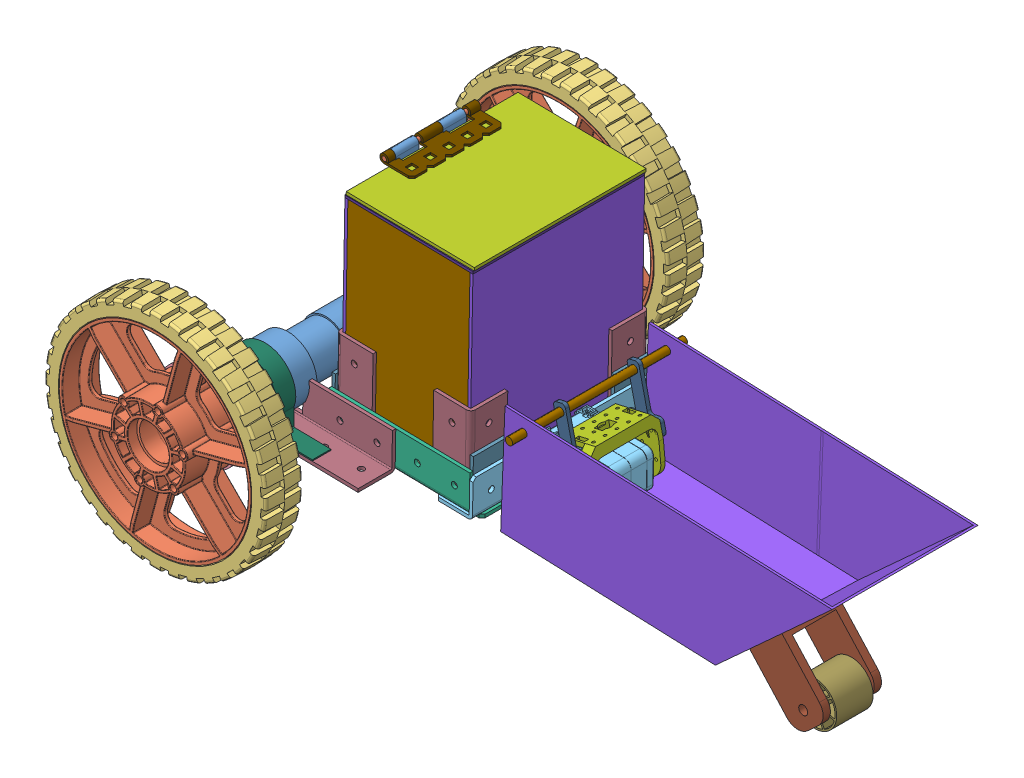
SolidWorks assembly Minibot Alpha 7-2-2016, configuration Default. Lengths in mm.
Overall size (457.85 221.49 310.96).
56 component instances, 34 part files, 61 mates.
Components (placement in the parent):
- Mock Motor-1: Mock Motor [Default] at origin size (40 40 101.3)
- Tetrix 6in High Grip Wheel-1: Tetrix 6in High Grip Wheel [Default] at (23.1432 -3.1947 4.3821) x (0 0 1) z (-0.961609 -0.274424 0) size (61.33 152.4 152.4)
  - 6 wheel Rev 4-1: 6 wheel Rev 4 [Default] at (-52.6446 9.4231 21.378) size (34.93 132.08 132.08)
  - 6 wheel tread II-1: 6 wheel tread II [Default] at (-65.3446 9.4231 21.378) x (0 0 -1) z (1 0 0) size (152.4 152.4 25.58)
  - 6mm Hub-1: 6mm Hub [Default] at (-35.1821 9.4231 21.378) x (0 -0.999986 -0.005317) z (0 -0.005317 0.999986) size (58 26.4 58)
- Mock Motor-4: Mock Motor [Default] at (0 0 179.5) x (0.024429 0.999702 0) z (0 0 -1) size (40 40 101.3)
- Tetrix 6in High Grip Wheel-2: Tetrix 6in High Grip Wheel [Default] at (-18.2174 -14.6267 175.1179) x (0 0 -1) z (0.966044 0.258376 0) size (61.33 152.4 152.4)
  - 6 wheel Rev 4-1: 6 wheel Rev 4 [Default] at (-52.6446 9.4231 21.378) size (34.93 132.08 132.08)
  - 6 wheel tread II-1: 6 wheel tread II [Default] at (-65.3446 9.4231 21.378) x (0 0 -1) z (1 0 0) size (152.4 152.4 25.58)
  - 6mm Hub-1: 6mm Hub [Default] at (-35.1821 9.4231 21.378) x (0 -0.999986 -0.005317) z (0 -0.005317 0.999986) size (58 26.4 58)
- Frame Front Bar-1: Frame Front Bar [Default] at (27.9803 -24.6073 774.7) x (0.999827 -0.018619 0) z (0 0 1) size (25.4 25.4 127)
- Frame Side Bar-1: Frame Side Bar [Default] at (777.1929 -36.2725 152.4) x (0 0 -1) z (0.999827 -0.018619 0) size (25.4 25.4 97.03)
- Frame Side Bar-2: Frame Side Bar [Default] at (-619.5649 -10.2625 25.4) x (0 0 1) z (-0.999827 0.018619 0) size (25.4 25.4 97.03)
- Frame Front Bar-2: Frame Front Bar [Default] at (129.5627 -26.4989 -596.9) x (-0.999827 0.018619 0) z (0 0 -1) size (25.4 25.4 127)
- Brain Box-1: Brain Box [Default] at (35.139 -11.5303 147.828) x (0.999827 -0.018619 0) z (0 0 1) size (98.42 141.04 122.4)
  - Bottom Brain Box Plate-1: Bottom Brain Box Plate [Default] at origin size (87.83 2.03 117.83)
  - Side Brain Box Plate-2: Side Brain Box Plate [Default] at (85.796 0 4.572) size (2.03 127 117.83)
  - Brain Box Front Plate-1: Brain Box Front Plate [Default] at origin
  - Side Brain Box Plate-3: Side Brain Box Plate [Default] at (0 0 4.572) size (2.03 127 117.83)
  - Brain Box Front Plate Real-1: Brain Box Front Plate Real [Default] at origin size (83.76 127 2.03)
  - Brain Box Front Plate Real-2: Brain Box Front Plate Real [Default] at (0 0 -115.796) size (83.76 127 2.03)
  - Breadboard-1: Breadboard [Default] at (85.796 18.0502 -33.0464) x (0 1 0) z (0 0 1) size (86.36 9.65 55.88)
  - ESP Breakout-1: ESP Breakout [Default] at (76.144 55.9536 -42.2125) x (0 1 0) z (0 0 1) size (38 5 25)
  - TSR12450-1: TSR12450 [Default] at (65.944 80.1193 -73.0785) x (0 -1 0) z (0 0 1) size (11.7 10.2 7.6)
  - Brain Box Connector-12: Brain Box Connector [Default] at (-2.286 -624.586 2.286) x (0 0 -1) z (0 -1 0) size (25.4 25.4 48.51)
  - Brain Box Connector 1in-6: Brain Box Connector 1in [Default] at (-4.572 -2.286 649.986) size (25.4 25.4 25.4)
  - Brain Box Connector-13: Brain Box Connector [Default] at (-2.286 -624.586 -120.114) x (1 0 0) z (0 -1 0) size (25.4 25.4 48.51)
  - Brain Box Connector 1in-7: Brain Box Connector 1in [Default] at (-4.572 -2.286 552.986) size (25.4 25.4 25.4)
  - Brain Box Connector-14: Brain Box Connector [Default] at (90.114 -624.586 -120.114) x (0 0 1) z (0 -1 0) size (25.4 25.4 48.51)
  - Brain Box Connector 1in-8: Brain Box Connector 1in [Default] at (92.4 -2.286 -767.814) x (-1 0 0) z (0 0 -1) size (25.4 25.4 25.4)
  - Brain Box Connector-15: Brain Box Connector [Default] at (90.114 -624.586 2.286) x (-1 0 0) z (0 -1 0) size (25.4 25.4 48.51)
  - Brain Box Connector 1in-9: Brain Box Connector 1in [Default] at (92.4 -2.286 -670.814) x (-1 0 0) z (0 0 -1) size (25.4 25.4 25.4)
  - Fuse Box-1: Fuse Box [Default] at (7.9055 2.032 -40.132) x (1 0 0) z (0 -1 0) size (63.5 38.1 86.36)
  - Battery-1: Battery [Default] at (30.032 2.032 -94.6088) x (0 0 1) z (0 -1 0) size (36 28 107)
  - Brain Box Dust Protector-1: Brain Box Dust Protector [Default] at origin size (87.83 1.59 117.83)
  - Hinge Part 1-1: Hinge Part 1 [Default] at (12.8755 132.7707 -61.5286) x (0.999994 0.003505 0) z (0 0 1) size (22.03 5.97 63.5)
  - Hinge Part 2-1: Hinge Part 2 [Default] at (0 119.8245 -58.9719) x (0 -1 0) z (0 0 -1) size (22.06 6.02 63.5)
  - Hinge Pin-1: Hinge Pin [Default] at (-3.0099 135.6995 -93.2786) size (3.17 3.17 63.5)
  - Bottom Brain Box Plate-2: Bottom Brain Box Plate [Default] at (0.4687 130.6952 -0.3832) x (0.999994 0.003505 0) z (0 0 1) size (87.83 2.03 117.83)
- Rubber Mount-1: Rubber Mount [Default] at (-55.0762 12.6992 -22.9404) x (0.999827 -0.018619 0) z (0 0 1) size (97.03 6.35 22.3)
- Rubber Mount-2: Rubber Mount [Default] at (-55.0762 12.6992 76.3736) x (0.999827 -0.018619 0) z (0 0 1) size (97.03 6.35 22.3)
- AX12 Servo-1: AX12 Servo [Default] at (146.6838 -2.3793 62.3741) x (0 0 1) z (0.018619 0.999827 0) size (40.85 52.72 32)
  - ax12_wheel-1: ax12_wheel [Default] at (44.532 15.8309 -11.4342) x (0 0.360476 -0.932769) z (0 -0.932769 -0.360476) size (22 14.85 22)
  - ax12_box-1: ax12_box [Default] at (25.532 3.8309 -11.4342) x (0 -1 0) z (0 0 -1) size (50 38.01 32)
- 90deg Gusset-1: 90deg Gusset [Default] at (116.8223 -28.5481 88.9) x (0.999827 -0.018619 0) z (0.018619 0.999827 0) size (69.6 69.6 2.29)
- F2-1: F2 [Default] at (162.2991 -14.1063 87.9061) x (-0.974309 -0.225213 0) z (0 0 1) size (25 37.5 48.5)
- Scoop Shell-1: Scoop Shell [Default] at (256.1616 -40.3352 39.711) x (0 0 1) z (-0.999245 0.038863 0) size (100 105.01 224.62)
- Scoop Pin-1: Scoop Pin [Default] at (151.9167 30.8094 149.711) x (0.006513 -0.999979 0) z (0.999979 0.006513 0) size (5 120 5)
- Scoop Servo Holder-1: Scoop Servo Holder [Default] at (171.9781 -0.4763 111.9061) x (-0.225213 0.974309 0) z (0.974309 0.225213 0) size (40 2.5 25)
- Scoop Servo Holder-2: Scoop Servo Holder [Default] at (147.6203 -6.1066 63.9061) x (-0.225213 0.974309 0) z (-0.974309 -0.225213 0) size (40 2.5 25)
- Mock Caster Wheel Holder-1: Mock Caster Wheel Holder [Default] at (297.874 -28.3041 69.711) x (0 0 1) z (0.738627 0.674114 0) size (40 50 30)
- Mock Caster Wheel-1: Mock Caster Wheel [Default] at (313.7592 -67.9609 76.711) size (30 30 25)
- Motor Mount Connector Left-1: Motor Mount Connector Left [Default] at (701.0062 -34.8538 152.4) x (0.018619 0.999827 0) z (0.999827 -0.018619 0) size (27.73 25.4 127.88)
- Motor Mount Connector Right-1: Motor Mount Connector Right [Default] at (-670.3561 -9.3166 25.4) x (0.018619 0.999827 0) z (-0.999827 0.018619 0) size (25.4 25.4 124.71)
- 1 1-2 inch Pipe Strap-1: 1 1-2 inch Pipe Strap [Default] x (0.999827 -0.018619 0) z (0 0 1) size (90.96 40.62 12.7)
- 1 1-2 inch Pipe Strap-2: 1 1-2 inch Pipe Strap [Default] at (0 0 177.8) x (-0.999827 0.018619 0) z (0 0 -1) size (90.96 40.62 12.7)
Mates (geometry in assembly coordinates):
- Concentric1: concentric aligned: cylinder of Mock Motor-1 through (0 0 -20.3) axis (0 0 1) radius 3; cylinder of Tetrix 6in High Grip Wheel-1/6mm Hub-1 through (0 0 -44.612) axis (0 0 1) radius 3
- Distance1: distance = 4.4 mm anti-aligned: plane of Tetrix 6in High Grip Wheel-1/6mm Hub-1 through (0 0 -4.4) normal (0 0 1); plane of Mock Motor-1 through (0 0 0) normal (0 0 -1)
- Concentric2: concentric anti-aligned: cylinder of Mock Motor-1 through (0 0 81) axis (0 0 -1) radius 15; cylinder of Mock Motor-4 through (0 0 98.5) axis (0 0 1) radius 15
- Distance2: distance = 17.5 mm anti-aligned: plane of Mock Motor-1 through (0 0 81) normal (0 0 1); plane of Mock Motor-4 through (0 0 98.5) normal (0 0 -1)
- Concentric4: concentric aligned: cylinder of Mock Motor-4 through (0 0 199.8) axis (0 0 -1) radius 3; cylinder of Tetrix 6in High Grip Wheel-2/6mm Hub-1 through (0 0 224.112) axis (0 0 -1) radius 3
- Distance3: distance = 4.4 mm anti-aligned: plane of Tetrix 6in High Grip Wheel-2/6mm Hub-1 through (0 0 183.9) normal (0 0 -1); plane of Mock Motor-4 through (0 0 179.5) normal (0 0 1)
- Concentric5: concentric aligned: cylinder of Frame Front Bar-1 through (40.6781 -24.8437 139.7) axis (-0.018619 -0.999827 0) radius 2.0701; cylinder of Frame Side Bar-1 through (40.7206 -22.5581 139.7) axis (-0.018619 -0.999827 0) radius 2.0701
- Coincident5: coincident anti-aligned: plane of Frame Front Bar-1 through (53.4184 -22.7946 1524) normal (0.018619 0.999827 0); plane of Frame Side Bar-1 through (28.0228 -22.3217 127) normal (-0.018619 -0.999827 0)
- Perpendicular1: perpendicular: plane of Frame Front Bar-1 through (27.9803 -24.6073 774.7) normal (-0.999827 0.018619 0); plane of Frame Side Bar-1 through (777.1929 -36.2725 152.4) normal (0 0 1)
- Concentric6: concentric aligned: cylinder of Frame Front Bar-1 through (40.6781 -24.8437 38.1) axis (-0.018619 -0.999827 0) radius 2.0701; cylinder of Frame Side Bar-2 through (40.7206 -22.5581 38.1) axis (-0.018619 -0.999827 0) radius 2.0701
- Coincident7: coincident anti-aligned: plane of Frame Front Bar-1 through (53.4184 -22.7946 1524) normal (0.018619 0.999827 0); plane of Frame Side Bar-2 through (129.6052 -24.2133 50.8) normal (-0.018619 -0.999827 0)
- Perpendicular2: perpendicular: plane of Frame Front Bar-1 through (27.9803 -24.6073 774.7) normal (-0.999827 0.018619 0); plane of Frame Side Bar-2 through (-619.5649 -10.2625 25.4) normal (0 0 -1)
- Concentric8: concentric aligned: cylinder of Frame Side Bar-1 through (116.9074 -23.9769 139.7) axis (-0.018619 -0.999827 0) radius 2.0701; cylinder of Frame Front Bar-2 through (116.8649 -26.2625 139.7) axis (-0.018619 -0.999827 0) radius 2.0701
- Coincident11: coincident anti-aligned: plane of Frame Side Bar-1 through (28.0228 -22.3217 127) normal (-0.018619 -0.999827 0); plane of Frame Front Bar-2 through (104.2096 -23.7404 -1346.2) normal (0.018619 0.999827 0)
- Concentric9: concentric aligned: cylinder of Frame Side Bar-2 through (116.9074 -23.9769 38.1) axis (-0.018619 -0.999827 0) radius 2.0701; cylinder of Frame Front Bar-2 through (116.8649 -26.2625 38.1) axis (-0.018619 -0.999827 0) radius 2.0701
- Coincident14: coincident anti-aligned: plane of Frame Side Bar-1 through (1526.4056 -47.9378 127) normal (0.018619 0.999827 0); plane of Rubber Mount-2 through (-55.6568 -18.477 76.3736) normal (-0.018619 -0.999827 0)
- Coincident15: coincident anti-aligned: plane of Frame Front Bar-2 through (127.3196 -24.1708 -1346.2) normal (-0.999827 0.018619 0); plane of Rubber Mount-2 through (127.4804 -15.5363 150.114) normal (0.999827 -0.018619 0)
- Coincident16: coincident anti-aligned: plane of Frame Side Bar-1 through (1526.4056 -47.9378 150.114) normal (0 0 -1); plane of Rubber Mount-2 through (30.4692 -13.7297 150.114) normal (0 0 1)
- Coincident17: coincident anti-aligned: plane of Brain Box-1/Brain Box Connector 1in-8 through (102.0848 -15.0633 129.314) normal (-0.018619 -0.999827 0); plane of Rubber Mount-1 through (-55.5386 -12.1281 -22.9404) normal (0.018619 0.999827 0)
- Coincident18: coincident anti-aligned: plane of Frame Front Bar-2 through (127.3196 -24.1708 -1346.2) normal (-0.999827 0.018619 0); plane of Brain Box-1/Brain Box Connector 1in-8 through (127.4804 -15.5363 -619.986) normal (0.999827 -0.018619 0)
- Coincident19: coincident anti-aligned: plane of Frame Side Bar-2 through (-1368.6925 5.974 50.8) normal (0.018619 0.999827 0); plane of Rubber Mount-1 through (-55.6568 -18.477 -22.9404) normal (-0.018619 -0.999827 0)
- Coincident21: coincident anti-aligned: plane of Frame Front Bar-1 through (30.3084 -22.3642 1524) normal (0.999827 -0.018619 0); plane of Rubber Mount-1 through (30.4692 -13.7297 50.8) normal (-0.999827 0.018619 0)
- Coincident22: coincident anti-aligned: plane of Frame Side Bar-1 through (1526.4056 -47.9378 150.114) normal (0 0 -1); plane of Brain Box-1/Brain Box Connector-12 through (21.2245 -635.9655 150.114) normal (0 0 1)
- Coincident24: coincident anti-aligned: plane of Frame Front Bar-2 through (104.1671 -26.026 152.4) normal (-0.018619 -0.999827 0); plane of 90deg Gusset-1 through (136.0385 -26.6195 108.077) normal (0.018619 0.999827 0)
- Concentric10: concentric aligned: cylinder of Frame Front Bar-2 through (116.8649 -26.2625 88.9) axis (-0.018619 -0.999827 0) radius 2.0701; cylinder of 90deg Gusset-1 through (116.8649 -26.2625 88.9) axis (-0.018619 -0.999827 0) radius 2.0701
- Concentric11: concentric aligned: cylinder of Frame Front Bar-2 through (116.8649 -26.2625 139.7) axis (-0.018619 -0.999827 0) radius 2.0701; cylinder of 90deg Gusset-1 through (116.8649 -26.2625 139.7) axis (-0.018619 -0.999827 0) radius 2.0701
- Coincident25: coincident anti-aligned: plane of AX12 Servo-1/ax12_box-1 through (173.555 -27.3181 71.9061) normal (-0.018619 -0.999827 0); plane of 90deg Gusset-1 through (136.0385 -26.6195 108.077) normal (0.018619 0.999827 0)
- Distance4: distance = 0.323 mm aligned: plane of AX12 Servo-1/ax12_box-1 through (174.0391 -1.3226 71.9061) normal (0.999827 -0.018619 0); plane of 90deg Gusset-1 through (173.878 -27.3242 78.486) normal (0.999827 -0.018619 0)
- Distance5: distance = 5.1791 mm aligned: plane of 90deg Gusset-1 through (171.7193 -27.284 101.727) normal (0 0 1); plane of AX12 Servo-1/ax12_box-1 through (162.2991 -14.1063 106.9061) normal (0 0 1)
- Coincident29: coincident anti-aligned: plane of AX12 Servo-1/ax12_wheel-1 through (162.2991 -14.1063 108.9061) normal (0 0 1); plane of F2-1 through (181.8411 -21.0045 108.9061) normal (0 0 -1)
- Concentric14: concentric aligned: circle of AX12 Servo-1/ax12_wheel-1; cylinder of F2-1 through (162.2991 -14.1063 111.9061) axis (0 0 -1) radius 4
- Concentric15: concentric anti-aligned: cylinder of Scoop Shell-1 through (151.9167 30.8094 297.171) axis (0 0 -1) radius 2.5; cylinder of Scoop Pin-1 through (151.9167 30.8094 22.5835) axis (0 0 1) radius 2.5
- Distance7: distance = 10 mm aligned: plane of Scoop Pin-1 through (151.9167 30.8094 149.711) normal (0 0 1); plane of Scoop Shell-1 through (259.123 35.8072 139.711) normal (0 0 1)
- Concentric16: concentric anti-aligned: cylinder of F2-1 through (150.9012 -0.319 63.6561) axis (0 0 1) radius 1; cylinder of Scoop Servo Holder-1 through (150.9012 -0.319 114.4061) axis (0 0 -1) radius 1
- Concentric17: concentric anti-aligned: cylinder of F2-1 through (166.4901 3.2844 63.6561) axis (0 0 1) radius 1; cylinder of Scoop Servo Holder-1 through (166.4901 3.2844 114.4061) axis (0 0 -1) radius 1
- Coincident35: coincident anti-aligned: plane of F2-1 through (162.2991 -14.1063 111.9061) normal (0 0 1); plane of Scoop Servo Holder-1 through (171.9781 -0.4763 111.9061) normal (0 0 -1)
- Concentric18: concentric aligned: cylinder of F2-1 through (166.4901 3.2844 63.6561) axis (0 0 1) radius 1; cylinder of Scoop Servo Holder-2 through (166.4901 3.2844 61.4061) axis (0 0 1) radius 1
- Concentric19: concentric aligned: cylinder of F2-1 through (150.9012 -0.319 63.6561) axis (0 0 1) radius 1; cylinder of Scoop Servo Holder-2 through (150.9012 -0.319 61.4061) axis (0 0 1) radius 1
- Coincident36: coincident anti-aligned: plane of F2-1 through (162.2991 -14.1063 63.9061) normal (0 0 -1); plane of Scoop Servo Holder-2 through (147.6203 -6.1066 63.9061) normal (0 0 1)
- Concentric20: concentric anti-aligned: cylinder of Scoop Pin-1 through (151.9167 30.8094 22.5835) axis (0 0 1) radius 2.5; cylinder of Scoop Servo Holder-1 through (151.9167 30.8094 114.4061) axis (0 0 -1) radius 2.5
- Coincident38: coincident anti-aligned: plane of Scoop Shell-1 through (269.1265 -54.5408 -137.004) normal (0.674114 -0.738627 0); plane of Mock Caster Wheel Holder-1 through (297.874 -28.3041 62.5835) normal (-0.674114 0.738627 0)
- Distance9: distance = 70 mm anti-aligned: plane of Scoop Shell-1 through (259.123 35.8072 139.711) normal (0 0 1); plane of Mock Caster Wheel Holder-1 through (331.5797 -65.2354 69.711) normal (0 0 -1)
- Concentric21: concentric aligned: cylinder of Mock Caster Wheel Holder-1 through (313.7592 -67.9609 47.5835) axis (0 0 1) radius 3.0831; cylinder of Mock Caster Wheel-1 through (313.7592 -67.9609 69.5835) axis (0 0 1) radius 4
- Distance10: distance = 3 mm anti-aligned: plane of Mock Caster Wheel-1 through (313.7592 -67.9609 101.711) normal (0 0 1); plane of Mock Caster Wheel Holder-1 through (309.4209 -85.4588 104.711) normal (0 0 -1)
- Distance11: distance = 89.073 mm: plane of Mock Caster Wheel Holder-1 through (331.5797 -65.2354 69.711) normal (0.738627 0.674114 0); line of Scoop Shell-1 through (363.6658 31.7413 139.711) axis (0 0 -1)
- Concentric26: concentric anti-aligned: cylinder of Frame Side Bar-1 through (66.3527 -10.3332 152.4) axis (0 0 1) radius 2.0701; cylinder of Motor Mount Connector Left-1 through (66.3527 -10.3332 152.4) axis (0 0 -1) radius 2.0701
- Coincident45: coincident anti-aligned: plane of Frame Side Bar-1 through (777.1929 -36.2725 152.4) normal (0 0 1); plane of Motor Mount Connector Left-1 through (-47.6911 4.4926 152.4) normal (0 0 -1)
- Concentric27: concentric anti-aligned: cylinder of Frame Side Bar-1 through (40.9571 -9.8603 152.4) axis (0 0 1) radius 2.0701; cylinder of Motor Mount Connector Left-1 through (40.9571 -9.8603 152.4) axis (0 0 -1) radius 2.0701
- Coincident46: coincident anti-aligned: plane of Frame Side Bar-2 through (-619.5649 -10.2625 25.4) normal (0 0 -1); plane of Motor Mount Connector Right-1 through (79.2869 2.1281 25.4) normal (0 0 1)
- Concentric28: concentric anti-aligned: cylinder of Frame Side Bar-2 through (66.3527 -10.3332 25.4) axis (0 0 -1) radius 2.0701; cylinder of Motor Mount Connector Right-1 through (66.3527 -10.3332 25.4) axis (0 0 1) radius 2.0701
- Concentric29: concentric anti-aligned: cylinder of Frame Side Bar-2 through (40.9571 -9.8603 25.4) axis (0 0 -1) radius 2.0701; cylinder of Motor Mount Connector Right-1 through (40.9571 -9.8603 25.4) axis (0 0 1) radius 2.0701
- Coincident47: coincident aligned: plane of Mock Motor-1 through (0 0 0) normal (0 0 -1); plane of Motor Mount Connector Right-1 through (-1419.0533 30.0298 0) normal (0 0 -1)
- Concentric31: concentric aligned: cylinder of Mock Motor-1 through (0 0 30) axis (0 0 -1) radius 20; cylinder of 1 1-2 inch Pipe Strap-1 through (0 0 12.7) axis (0 0 -1) radius 20.32
- Coincident50: coincident anti-aligned: plane of Motor Mount Connector Right-1 through (-1419.4836 6.9198 23.114) normal (0.018619 0.999827 0); plane of 1 1-2 inch Pipe Strap-1 through (-0.3632 -19.5067 12.7) normal (-0.018619 -0.999827 0)
- Coincident51: coincident aligned: plane of Motor Mount Connector Right-1 through (-1419.0533 30.0298 0) normal (0 0 -1); plane of 1 1-2 inch Pipe Strap-1 through (0 0 0) normal (0 0 -1)
- Concentric32: concentric aligned: cylinder of Mock Motor-4 through (0 0 149.5) axis (0 0 1) radius 20; cylinder of 1 1-2 inch Pipe Strap-2 through (0 0 165.1) axis (0 0 1) radius 20.32
- Coincident52: coincident anti-aligned: plane of Motor Mount Connector Left-1 through (1450.2188 -46.5191 154.686) normal (0.018619 0.999827 0); plane of 1 1-2 inch Pipe Strap-2 through (-0.3632 -19.5067 165.1) normal (-0.018619 -0.999827 0)
- Coincident53: coincident aligned: plane of Motor Mount Connector Left-1 through (1450.6492 -23.4091 177.8) normal (0 0 1); plane of 1 1-2 inch Pipe Strap-2 through (0 0 177.8) normal (0 0 1)
- Coincident54: coincident aligned: plane of Motor Mount Connector Right-1 through (-45.8784 -20.9455 25.4) normal (-0.999827 0.018619 0); plane of 1 1-2 inch Pipe Strap-1 through (-45.4725 0.8468 12.7) normal (-0.999827 0.018619 0)
- Coincident55: coincident aligned: plane of Frame Side Bar-2 through (-619.5649 -10.2625 50.8) normal (0 0 1); plane of Rubber Mount-1 through (30.4692 -13.7297 50.8) normal (0 0 1)
- Distance12: distance = 89.789 mm: plane of Mock Motor-4 through (0 0 179.5) normal (0 0 1); line of Scoop Shell-1 through (253.4555 -69.0656 89.711) axis (-0.999245 0.038863 0)
